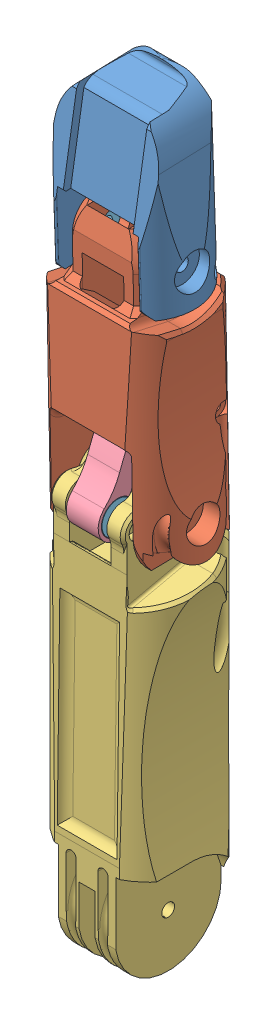
SolidWorks assembly assembly ring finger, configuration Default. Lengths in mm.
Overall size (26.38 120.07 19.08).
12 component instances, 5 part files, 24 mates.
Components (placement in the parent):
- ring link1-1: ring link1 [Default] at (0 -16.6207 -27.0759) x (1 0 0) z (0 -0.035101 0.999384) size (19.5 27.22 13.31)
- ring link2-1: ring link2 [Default] at (0 -50.7246 -27.7198) x (1 0 0) z (0 -0.018878 0.999822) size (23.68 44.11 15.32)
- ring link3-1: ring link3 [Default] at (0 -105.9146 -27.7198) size (26.38 68.5 18.99)
- ring linkage-1: ring linkage [Default] at (0 -34.3209 -27.4381) x (1 0 0) z (0 0.999852 0.017227) size (5 17.7 37.06)
- bearing 1.5-4-5-2-3: bearing 1.5-4-5-2 [Default] at (0.5 -50.7246 -21.8498) x (0 -0.99212 0.125289) z (0 0.125289 0.99212) size (5 2 5)
- bearing 1.5-4-5-2-4: bearing 1.5-4-5-2 [Default] at (4.35 -50.7246 -27.7198) x (0 -0.99212 0.125289) z (0 0.125289 0.99212) size (5 2 5)
- bearing 1.5-4-5-2-5: bearing 1.5-4-5-2 [Default] at (-4.35 -50.7246 -27.7198) x (0 0.62728 0.778794) z (0 -0.778794 0.62728) size (5 2 5)
- bearing 1.5-4-5-2-6: bearing 1.5-4-5-2 [Default] at (-0.5 -50.7246 -21.8498) x (0 0.62728 0.778794) z (0 -0.778794 0.62728) size (5 2 5)
- bearing 1.5-4-5-2-7: bearing 1.5-4-5-2 [Default] at (0.5 -19.6711 -32.8157) x (0 -0.99212 0.125289) z (0 0.125289 0.99212) size (5 2 5)
- bearing 1.5-4-5-2-8: bearing 1.5-4-5-2 [Default] at (-0.5 -19.6711 -32.8157) x (0 0.62728 0.778794) z (0 -0.778794 0.62728) size (5 2 5)
- bearing 1.5-4-5-2-9: bearing 1.5-4-5-2 [Default] at (4.35 -16.6207 -27.0759) x (0 -0.99212 0.125289) z (0 0.125289 0.99212) size (5 2 5)
- bearing 1.5-4-5-2-10: bearing 1.5-4-5-2 [Default] at (-4.35 -16.6207 -27.0759) x (0 0.62728 0.778794) z (0 -0.778794 0.62728) size (5 2 5)
Mates (geometry in assembly coordinates):
- Coincident1: coincident: plane of assembly through (0 0 0) normal (1 0 0); plane of ring link3-1 through (0 -105.9146 -27.7198) normal (1 0 0); plane of assembly
- Concentric1: concentric: cylinder of assembly; cylinder of assembly; cylinder of ring link2-1 through (7.4 -50.7246 -27.7198) axis (1 0 0) radius 2.625; cylinder of ring link3-1 through (-10.4 -50.7246 -27.7198) axis (1 0 0) radius 2.55
- Width1: width: plane of assembly; plane of assembly; plane of assembly; plane of assembly; plane of ring link2-1 through (-6.4 -38.6116 -33.5922) normal (1 0 0); plane of ring link2-1 through (6.4 -38.6116 -33.5922) normal (-1 0 0); plane of ring link3-1 through (-5.75 -56.0246 -27.7198) normal (-1 0 0); plane of ring link3-1 through (5.75 -56.0246 -27.7198) normal (1 0 0)
- Concentric2: concentric: cylinder of assembly; cylinder of assembly; cylinder of ring link1-1 through (-10.0932 -16.6207 -27.0759) axis (1 0 0) radius 1; cylinder of ring link2-1 through (-10.4 -16.6207 -27.0759) axis (1 0 0) radius 2.55
- Width2: width: plane of assembly; plane of assembly; plane of assembly; plane of assembly; plane of ring link1-1 through (-6.4 12.2865 -26.0606) normal (1 0 0); plane of ring link1-1 through (6.4 12.2865 -26.0606) normal (-1 0 0); plane of ring link2-1 through (-5.75 -21.9198 -27.176) normal (-1 0 0); plane of ring link2-1 through (5.75 -21.9198 -27.176) normal (1 0 0)
- Concentric3: concentric: cylinder of assembly; cylinder of assembly; cylinder of ring link3-1 through (-10.8126 -50.7246 -21.8498) axis (1 0 0) radius 0.65; cylinder of ring linkage-1 through (2.5 -50.7246 -21.8498) axis (-1 0 0) radius 2.075
- Width3: width: plane of ring link3-1 through (3.25 -110.9146 -33.8198) normal (-1 0 0); plane of ring link3-1 through (-3.25 -110.9146 -33.8198) normal (1 0 0); plane of ring linkage-1 through (2.5 -34.3209 -27.4381) normal (1 0 0); plane of ring linkage-1 through (-2.5 -34.3209 -27.4381) normal (-1 0 0)
- Concentric4: concentric: cylinder of ring link1-1 through (-10.0465 -19.6711 -32.8157) axis (1 0 0) radius 0.7; cylinder of ring linkage-1 through (2.5 -19.6711 -32.8157) axis (-1 0 0) radius 2.075
- Concentric8: concentric: cylinder of assembly; cylinder of assembly; cylinder of ring link3-1 through (-10.4 -50.7246 -27.7198) axis (1 0 0) radius 2.55; cylinder of bearing 1.5-4-5-2-4 through (6.35 -50.7246 -27.7198) axis (-1 0 0) radius 2
- Coincident4: coincident: plane of ring link3-1 through (5.75 -56.0246 -27.7198) normal (1 0 0); plane of bearing 1.5-4-5-2-4 through (5.75 -50.7246 -27.7198) normal (-1 0 0)
- Concentric9: concentric: cylinder of assembly; cylinder of assembly; cylinder of ring link3-1 through (-10.8126 -50.7246 -21.8498) axis (1 0 0) radius 0.65; cylinder of bearing 1.5-4-5-2-3 through (2.5 -50.7246 -21.8498) axis (-1 0 0) radius 2
- Coincident5: coincident: plane of ring linkage-1 through (1.9 -50.7246 -21.8498) normal (1 0 0); plane of bearing 1.5-4-5-2-3 through (1.9 -50.7246 -21.8498) normal (-1 0 0)
- Concentric10: concentric: cylinder of assembly; cylinder of assembly; cylinder of ring link3-1 through (-10.4 -50.7246 -27.7198) axis (1 0 0) radius 2.55; cylinder of bearing 1.5-4-5-2-5 through (-6.35 -50.7246 -27.7198) axis (1 0 0) radius 2
- Coincident6: coincident: plane of ring link3-1 through (-5.75 -56.0246 -27.7198) normal (-1 0 0); plane of bearing 1.5-4-5-2-5 through (-5.75 -50.7246 -27.7198) normal (1 0 0)
- Concentric11: concentric: cylinder of assembly; cylinder of assembly; cylinder of ring link3-1 through (-10.8126 -50.7246 -21.8498) axis (1 0 0) radius 0.65; cylinder of bearing 1.5-4-5-2-6 through (-2.5 -50.7246 -21.8498) axis (1 0 0) radius 2
- Coincident7: coincident: plane of ring linkage-1 through (-1.9 -50.7246 -21.8498) normal (-1 0 0); plane of bearing 1.5-4-5-2-6 through (-1.9 -50.7246 -21.8498) normal (1 0 0)
- Concentric12: concentric: cylinder of ring linkage-1 through (2.5 -19.6711 -32.8157) axis (-1 0 0) radius 2.075; cylinder of bearing 1.5-4-5-2-7 through (2.5 -19.6711 -32.8157) axis (-1 0 0) radius 2
- Coincident8: coincident: plane of ring linkage-1 through (1.9 -19.6711 -32.8157) normal (1 0 0); plane of bearing 1.5-4-5-2-7 through (1.9 -19.6711 -32.8157) normal (-1 0 0)
- Concentric13: concentric: cylinder of ring linkage-1 through (2.5 -19.6711 -32.8157) axis (-1 0 0) radius 2.075; cylinder of bearing 1.5-4-5-2-8 through (-2.5 -19.6711 -32.8157) axis (1 0 0) radius 2
- Coincident9: coincident: plane of ring linkage-1 through (-1.9 -19.6711 -32.8157) normal (-1 0 0); plane of bearing 1.5-4-5-2-8 through (-1.9 -19.6711 -32.8157) normal (1 0 0)
- Concentric14: concentric: cylinder of assembly; cylinder of assembly; cylinder of ring link2-1 through (-10.4 -16.6207 -27.0759) axis (1 0 0) radius 2.55; cylinder of bearing 1.5-4-5-2-10 through (-6.35 -16.6207 -27.0759) axis (1 0 0) radius 2
- Coincident10: coincident: plane of ring link2-1 through (-5.75 -21.9198 -27.176) normal (-1 0 0); plane of bearing 1.5-4-5-2-10 through (-5.75 -16.6207 -27.0759) normal (1 0 0)
- Concentric15: concentric: cylinder of assembly; cylinder of assembly; cylinder of ring link2-1 through (-10.4 -16.6207 -27.0759) axis (1 0 0) radius 2.55; cylinder of bearing 1.5-4-5-2-9 through (6.35 -16.6207 -27.0759) axis (-1 0 0) radius 2
- Coincident11: coincident: plane of ring link2-1 through (5.75 -21.9198 -27.176) normal (1 0 0); plane of bearing 1.5-4-5-2-9 through (5.75 -16.6207 -27.0759) normal (-1 0 0)
